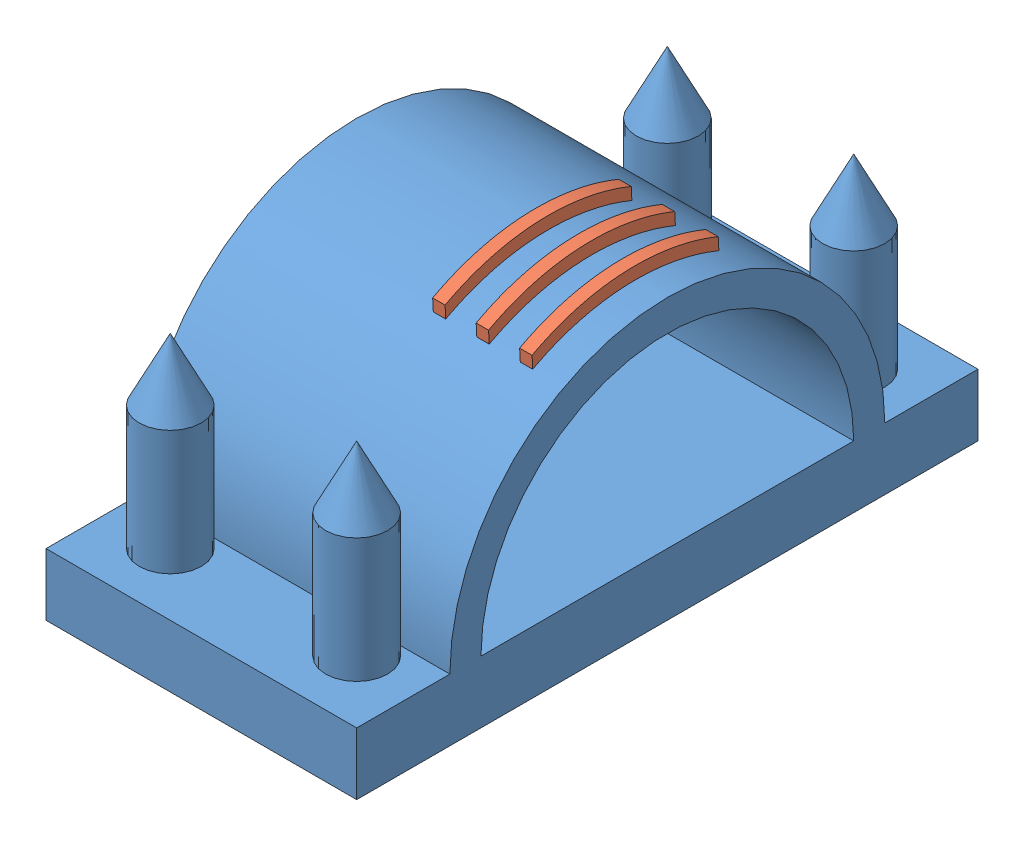
SolidWorks assembly Assem2, configuration Default. Lengths in mm.
Overall size (50 48.36 100).
4 component instances, 2 part files, 14 mates.
Components (placement in the parent):
- conformal_substrate_top-1: conformal_substrate_top [Default] at (-15 -40 40) x (0 0 -1) z (1 0 0) size (100 45 50)
- single_line-1: single_line [Default] at (4 -29.9799 40.0481) x (0 0.051791 -0.998658) z (1 0 0) size (30.02 6 2.02)
- single_line-2: single_line [Default] at (-3 -29.9799 40.0481) x (0 0.051791 -0.998658) z (1 0 0) size (30.02 6 2.02)
- single_line-3: single_line [Default] at (-10 -29.9799 40.0481) x (0 0.051791 -0.998658) z (1 0 0) size (30.02 6 2.02)
Mates (geometry in assembly coordinates):
- Coincident1: coincident: point of conformal_substrate_top-1
- Tangent1: tangent anti-aligned: cylinder of conformal_substrate_top-1 through (-118.2624 -30 40) axis (1 0 0) radius 35; face of single_line-1
- Parallel1: parallel: line of conformal_substrate_top-1 through (-30 -30 5) axis (1 0 0); plane of single_line-1 through (3 2.3773 26.706) normal (0 0.051791 -0.998658)
- Parallel2: parallel: line of conformal_substrate_top-1 through (-30 -30 75) axis (1 0 0); plane of single_line-1 through (5 0.8236 56.6657) normal (0 -0.051791 0.998658)
- Distance1: distance = 5 mm aligned: plane of conformal_substrate_top-1 through (10 -30 -10) normal (1 0 0); plane of single_line-1 through (5 0.8236 56.6657) normal (1 0 0)
- Tangent2: tangent anti-aligned: cylinder of conformal_substrate_top-1 through (-118.2624 -30 40) axis (1 0 0) radius 35; edge_curve of single_line-2
- Distance2: distance = 5 mm anti-aligned: plane of single_line-2 through (-2 0.8236 56.6657) normal (1 0 0); plane of single_line-1 through (3 2.3773 26.706) normal (-1 0 0)
- Parallel4: parallel aligned: plane of single_line-1 through (5 0.8236 56.6657) normal (0 -0.051791 0.998658); plane of single_line-2 through (-2 0.8236 56.6657) normal (0 -0.051791 0.998658)
- Distance3: distance = 5 mm anti-aligned: plane of single_line-3 through (-9 0.8236 56.6657) normal (1 0 0); plane of single_line-2 through (-4 2.3773 26.706) normal (-1 0 0)
- Tangent3: tangent anti-aligned: cylinder of conformal_substrate_top-1 through (-118.2624 -30 40) axis (1 0 0) radius 35; edge_curve of single_line-3
- Coincident9: coincident aligned: plane of single_line-2 through (-4 2.3773 26.706) normal (0 0.051791 -0.998658); plane of single_line-3 through (-11 2.3773 26.706) normal (0 0.051791 -0.998658)
- Distance4: distance = 20 mm: plane of single_line-2 through (-4 2.3773 26.706) normal (0 0.051791 -0.998658); line of conformal_substrate_top-1 through (-30 -30 5) axis (1 0 0)
- Parallel6: parallel aligned: plane of conformal_substrate_top-1 through (-15 -30 40) normal (0 1 0)
- Parallel7: parallel anti-aligned: plane of conformal_substrate_top-1 through (-40 -30 -10) normal (0 0 -1)
